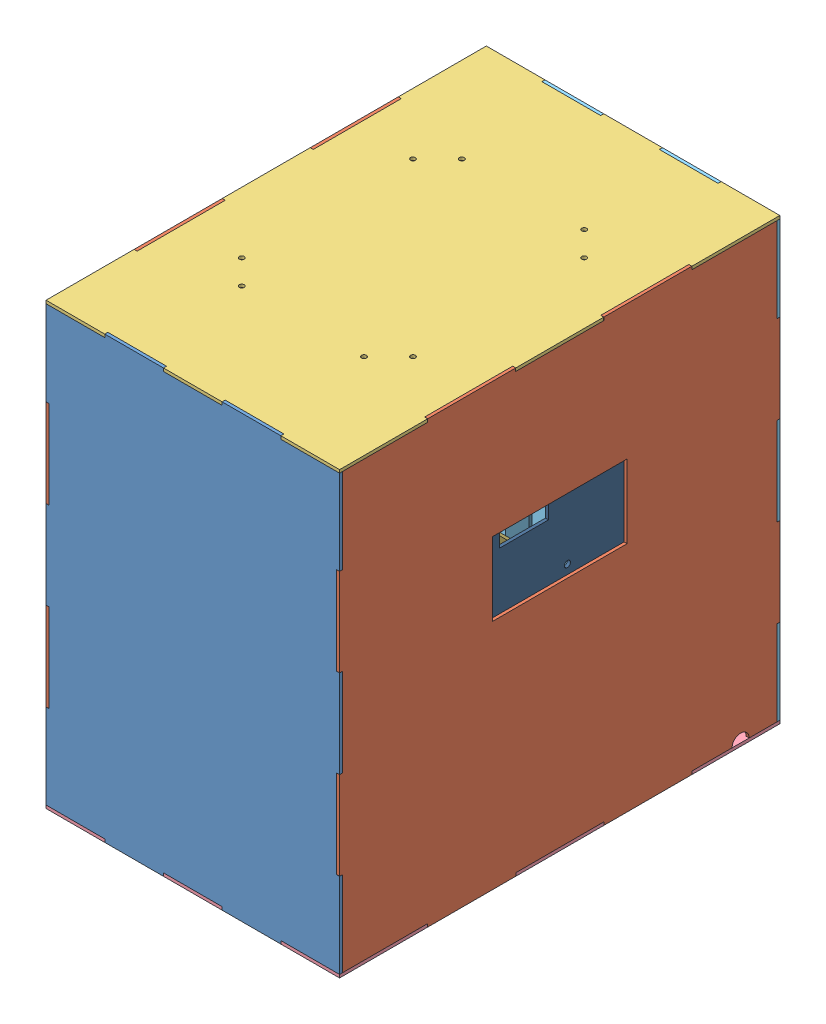
SolidWorks assembly OuterBoxAssembly, configuration Default. Lengths in mm.
Overall size (624.5 463.88 584.07).
19 component instances, 16 part files, 14 mates.
Components (placement in the parent):
- Pod Back-2: Pod Back [Default] at (-3.4714 -289.7079 369.9761) x (1 0 0) z (0 1 0) size (304.8 3.17 457.2)
- Pod Side 2-1: Pod Side 2 [Default] at (145.7536 -289.7077 141.2658) x (0 -1 0) z (0 0 1) size (457.2 3.17 457.2)
- Pod Side 2-2: Pod Side 2 [Default] at (-155.8714 -289.7168 141.3761) x (0 -1 0) z (0 0 1) size (457.2 3.17 457.2)
- Pod Top-1: Pod Top [Default] at (-3.4714 -64.2829 141.3761) size (304.8 3.17 457.2)
- Pod Base-1: Pod Base [Default] at (-3.4714 -518.3079 141.3761) size (304.8 3.17 457.2)
- Pod Front-5: Pod Front [Default] at (-3.4714 -289.7079 -84.0489) x (1 0 0) z (0 1 0) size (304.8 3.17 457.2)
- Insideboxassembly-1: Insideboxassembly [Default] at (-460.3025 -455.4397 335.419) x (-0.741694 -0.157321 0.652028) z (-0.605547 -0.260997 -0.751794) size (387.69 311.14 408.23)
  - inside box top-1: inside box top [Default] at (-509.6896 150.6083 -203.9396) x (0.652028 -0.098315 -0.751794) z (0.741694 0.28845 0.605547) size (279.4 3.17 228.6)
  - InnerBoxFront-2: InnerBoxFront [Default] at (-581.1313 58.122 -72.2069) x (0.741694 0.28845 0.605547) z (0.157321 -0.952434 0.260997) size (228.6 3.17 228.6) (hidden)
  - inside box side2-2: inside box side2 [Default] at (-409.7866 76.8231 -107.645) x (0.652028 -0.098315 -0.751794) z (0.157321 -0.952434 0.260997) size (279.4 3.17 228.6)
  - E128solderboard-3: E128solderboard [Default] at (-395.3637 -30.7401 -131.7484) x (0.741694 0.28845 0.605547) z (0.157321 -0.952434 0.260997) size (146.05 82.55 3.81)
  - BatteryHolder9V2-1: BatteryHolder9V2 [Default] at (-448.6593 -83.2 -230.2362) x (-0.652028 0.098315 0.751794) z (0.157321 -0.952434 0.260997) size (44.45 6.35 44.45)
  - BatteryHolder9V2-3: BatteryHolder9V2 [Default] at (-389.7873 -60.3043 -182.171) x (-0.652028 0.098315 0.751794) z (0.157321 -0.952434 0.260997) size (44.45 6.35 44.45)
  - InnerBoxBack-2: InnerBoxBack [Default] at (-403.1893 31.3466 -277.575) x (0.157321 -0.952434 0.260997) z (0.741694 0.28845 0.605547) size (228.6 3.17 228.6) (hidden)
  - inside box side1-1: inside box side1 [Default] at (-576.983 11.7993 -244.1503) x (0.652028 -0.098315 -0.751794) z (0.157321 -0.952434 0.260997) size (279.4 3.17 228.6)
  - inside box BOTTOM-1: inside box BOTTOM [Default] at (-474.7251 -61.0701 -145.933) x (-0.652028 0.098315 0.751794) z (0.741694 0.28845 0.605547) size (279.4 3.17 228.6)
  - ServoHolderHoles-1: ServoHolderHoles [Default] at (-535.694 -31.3874 -73.8537) x (0.741694 0.28845 0.605547) z (0.157321 -0.952434 0.260997) size (76.2 3.17 41.28)
  - ServoHolderNoHoles-1: ServoHolderNoHoles [Default] at (-525.343 -32.9481 -85.7884) x (0.741694 0.28845 0.605547) z (0.157321 -0.952434 0.260997) size (76.2 3.17 41.28)
  - arrow-1: arrow [Default] at (-684.8622 -261.4435 -156.2484) x (0.157321 -0.952434 0.260997) z (0.741694 0.28845 0.605547) size (101.6 3.17 39.37)
Mates (geometry in assembly coordinates):
- Coincident7: coincident anti-aligned: line of Pod Side 2-1 through (148.9286 -515.1329 4.1058) axis (0 -1 0); line of Pod Base-1 through (148.9286 -518.3079 4.1058) axis (0 1 0)
- Coincident9: coincident aligned: plane of Pod Side 2-1 through (148.9286 -289.7077 141.2658) normal (1 0 0); plane of Pod Base-1 through (148.9286 -515.1329 369.9761) normal (1 0 0)
- Coincident10: coincident anti-aligned: line of Pod Side 2-1 through (148.9286 -515.1329 -37.5927) axis (0 0 1); line of Pod Base-1 through (148.9286 -515.1329 4.1058) axis (0 0 -1)
- Coincident11: coincident aligned: line of Pod Side 2-2 through (-155.8714 -515.1329 278.5361) axis (0 0 1); line of Pod Base-1 through (-155.8714 -515.1329 278.5361) axis (0 0 1)
- Coincident12: coincident aligned: line of Pod Side 2-2 through (-155.8714 -518.3168 278.5361) axis (0 1 0); line of Pod Base-1 through (-155.8714 -518.3079 278.5361) axis (0 1 0)
- Coincident13: coincident anti-aligned: line of Pod Base-1 through (-94.9114 -515.1329 -87.2239) axis (-1 0 0); line of Pod Front-5 through (-155.8714 -515.1329 -87.2239) axis (1 0 0)
- Coincident14: coincident anti-aligned: line of Pod Base-1 through (-94.9114 -518.3079 -87.2239) axis (0 1 0); line of Pod Front-5 through (-94.9114 -515.1329 -87.2239) axis (0 -1 0)
- Coincident15: coincident aligned: line of Pod Back-2 through (-33.9514 -515.1329 369.9761) axis (1 0 0); line of Pod Base-1 through (-33.9514 -515.1329 369.9761) axis (1 0 0)
- Coincident17: coincident aligned: line of Pod Back-2 through (87.9686 -518.3079 369.9761) axis (0 1 0); line of Pod Base-1 through (87.9686 -518.3079 369.9761) axis (0 1 0)
- Coincident19: coincident anti-aligned: line of Pod Back-2 through (-94.9114 -61.1079 369.9761) axis (0 -1 0); line of Pod Top-1 through (-94.9114 -64.2829 369.9761) axis (0 1 0)
- Coincident20: coincident anti-aligned: line of Pod Back-2 through (27.0086 -64.2829 369.9761) axis (-1 0 0); line of Pod Top-1 through (-33.9514 -64.2829 369.9761) axis (1 0 0)
- Distance1: distance = 114.3 mm aligned: plane of Insideboxassembly-1/inside box top-1 through (-2.2168 -175.4079 141.6007) normal (0 1 0); plane of Pod Top-1 through (-3.4714 -61.1079 141.3761) normal (0 1 0)
- Concentric1: concentric aligned: circle of Pod Top-1; circle of Insideboxassembly-1/inside box top-1
- Concentric2: concentric aligned: circle of Pod Top-1; circle of Insideboxassembly-1/inside box top-1
